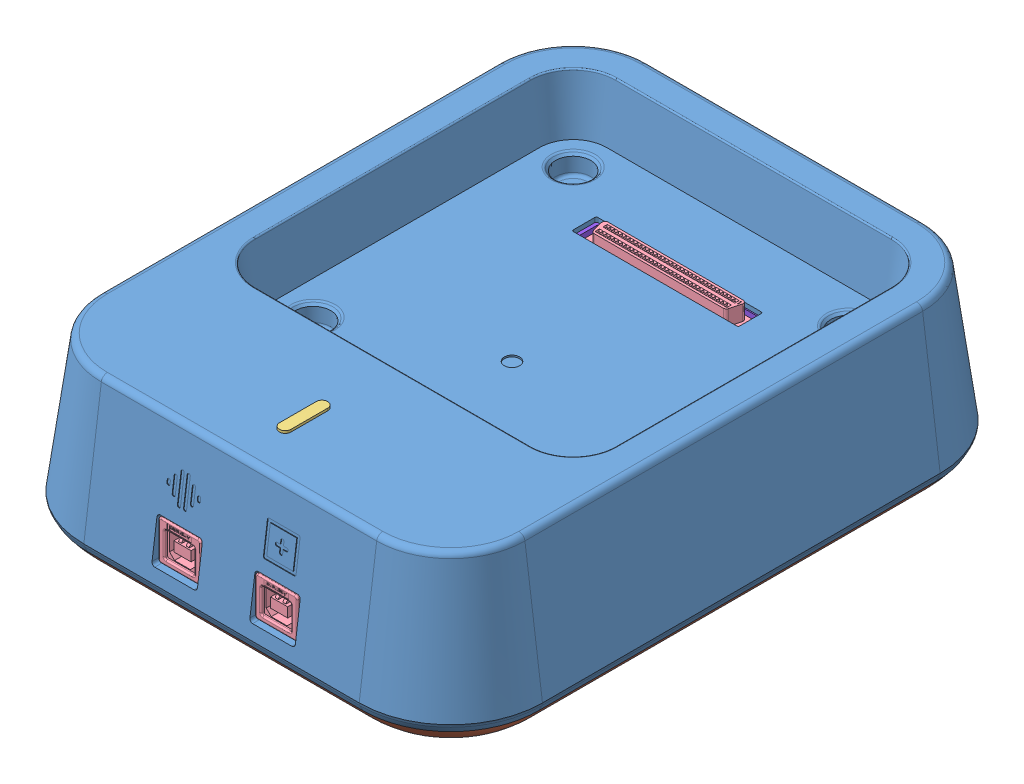
SolidWorks assembly 710-03064-01, configuration EXPLODE 1. Lengths in mm.
Overall size (149.92 60.49 189.92).
37 component instances, 15 part files, 52 mates.
Components (placement in the parent):
- 690-13322-01-1: 690-13322-01 [main top] at origin size (149.92 47.5 189.92)
- 690-13321-01-1: 690-13321-01 [amp bottom] at (0.0043 0.3144 -0.003) x (1 0 -0.000066) z (0.000066 0 1) size (147.12 44 187.12)
- 690-13335-01-1: 690-13335-01 [Default] at (0 42 68.125) x (0 0 -1) z (-1 0 0) size (40.5 22.51 15)
- 650-02461-01-2: 650-02461-01 [Default] at (37.5 19.7595 86.4) x (0 0 -1) z (0 1 0) size (161.48 77.75 25.95)
- 690-13430-01-4: 690-13430-01 [Default] at (-15.9372 11.6447 89.7779) x (0 -1 0) z (0 0 1) size (19.6 20.6 0.5)
- 690-13950-01-2: 690-13950-01 [Default] at (-1.9644 -41.2234 0.1742) size (194.82 1.78 194.82) (hidden)
- 690-13336-01-3: 690-13336-01 [Default] at (0.007 42 68.1256) x (0 0 -1) z (1 0 0) size (24.1 0.25 14.6)
- O-RING PLACE HOLDER-1: O-RING PLACE HOLDER [Default] at (5.773 -1.1006 6.1102) size (146.06 1.98 186.06)
- 690-13337-01-1: 690-13337-01 [Default] at (-0.132 23.2595 -50.5608) x (0.999997 0 -0.002288) z (0.002288 0 0.999997) size (68 5.5 14.5)
- 690-13430-01-5: 690-13430-01 [Default] at (15.7786 11.6447 89.878) x (0 -1 0) z (0 0 1) size (19.6 20.6 0.5)
- 250-06431-00-6: 250-06431-00 [99397A349] at (33.5 18.1525 -36.975) x (-0.159486 0 -0.9872) z (0 -1 0) size (5 5.25 8.76)
- 250-06431-00-8: 250-06431-00 [99397A349] at (33.5 18.1525 -64.5) x (-0.159486 0 -0.9872) z (0 -1 0) size (5 5.25 8.76)
- 250-06431-00-9: 250-06431-00 [99397A349] at (-33.5 18.1525 -36.975) x (0.943995 0 -0.329959) z (0 -1 0) size (5 5.25 8.76)
- 250-06431-00-10: 250-06431-00 [99397A349] at (-33.5 18.1525 -64.5) x (-0.159486 0 -0.9872) z (0 -1 0) size (5 5.25 8.76)
- 250-06431-00-11: 250-06431-00 [99397A349] at (33.5 18.1525 82.4) x (-0.159486 0 -0.9872) z (0 -1 0) size (5 5.25 8.76)
- 250-06431-00-13: 250-06431-00 [99397A349] at (-33.5 18.1525 82.4) x (-0.159486 0 -0.9872) z (0 -1 0) size (5 5.25 8.76)
- 250-06431-00-14: 250-06431-00 [99397A349] at (-33.5 18.1525 16.4) x (0.661999 0 0.749505) z (0 -1 0) size (5 5.25 8.76)
- 250-06431-00-17: 250-06431-00 [99397A349] at (33.5 18.1525 16.4) x (-0.159486 0 -0.9872) z (0 -1 0) size (5 5.25 8.76)
- 250-06430-00-6: 250-06430-00 [99397A484] at (-45 7.0739 -65) x (0.782317 0 -0.62288) z (0 -1 0) size (7 7.25 13.35)
- 250-06430-00-7: 250-06430-00 [99397A484] at (-44.9914 29.3144 65) x (0.782317 0 -0.62288) z (0 -1 0) size (7 7.25 13.35)
- 250-06430-00-11: 250-06430-00 [99397A484] at (45 7.0739 -65.0059) x (0.782317 0 -0.62288) z (0 -1 0) size (7 7.25 13.35)
- 250-06430-00-10: 250-06430-00 [99397A484] at (45.0086 29.3144 64.9941) x (0.782317 0 -0.62288) z (0 -1 0) size (7 7.25 13.35)
- 250-06431-00-1: 250-06431-00 [99397A349] at (-5 36.0263 82.6254) x (0.856632 0 0.515928) z (0 -1 0) size (5 5.25 8.76)
- 250-06431-00-2: 250-06431-00 [99397A349] at (5 36.0482 82.6254) x (-0.159486 0 -0.9872) z (0 -1 0) size (5 5.25 8.76)
- 250-06431-00-4: 250-06431-00 [99397A349] at (5 36.0507 48.125) x (-0.572843 0 -0.819665) z (0 -1 0) size (5 5.25 8.76)
- 250-06431-00-5: 250-06431-00 [99397A349] at (-5 36.0387 48.1246) x (0.649193 0 -0.760623) z (0 -1 0) size (5 5.25 8.76)
- 690-13338-01-2: 690-13338-01 [Default] at (45.0086 -11.4877 64.9941) x (0.945201 0 -0.326488) z (0.326488 0 0.945201) size (20 13 20)
- 690-13338-01-3: 690-13338-01 [Default] at (45 -11.4093 -65.0059) x (0.808095 0 -0.589052) z (0.589052 0 0.808095) size (20 13 20)
- 690-13338-01-4: 690-13338-01 [Default] at (-45 -11.4354 -65) x (0.796011 0 -0.605283) z (0.605283 0 0.796011) size (20 13 20)
- 690-13338-01-1: 690-13338-01 [Default] at (-44.9914 -11.3483 65) x (0.185576 0 -0.98263) z (0.98263 0 0.185576) size (20 13 20)
- 690-13885-01-1: 690-13885-01 [Default] at (45.0086 -4.7162 64.9941) size (18 0.5 18)
- 690-13885-01-2: 690-13885-01 [Default] at (45 -4.328 -65.0059) size (18 0.5 18)
- 690-13885-01-3: 690-13885-01 [Default] at (-45 -4.8227 -65) size (18 0.5 18)
- 690-13885-01-4: 690-13885-01 [Default] at (-44.9914 -2.7642 65) size (18 0.5 18)
- 961-00019-01-4: 961-00019-01 [Default] at (-0.2914 -12.1936 52.7077) x (-1 0 0.000066) z (0 -1 0) size (58.74 101.6 0.25)
  - 952-01439-01-1: 952-01439-01 [Default] at origin size (58.74 101.6 0.25)
  - 410-00892-00-1: 410-00892-00 [Default] at origin
Mates (geometry in assembly coordinates):
- Parallel2: parallel: plane of 650-02461-01-2 through (34.477 18.1525 86.397) normal (0 0 1); plane of assembly through (0 0 0) normal (0 0 1)
- Parallel3: parallel: plane of 650-02461-01-2 through (34.477 18.1525 86.397) normal (0 -1 0); plane of assembly through (0 0 0) normal (0 1 0)
- Concentric4: concentric: cylinder of 690-13337-01-1 through (30.8767 19.7595 -54.9003) axis (0 1 0) radius 2.9815; cylinder of 650-02461-01-2 through (30.8767 23.5822 -54.9003) axis (0 1 0) radius 1.016
- Coincident1: coincident: plane of 690-13337-01-1 through (-31.1407 19.7595 -46.2213) normal (0 -1 0); plane of 650-02461-01-2 through (34.477 19.7595 86.397) normal (0 1 0)
- Concentric5: concentric: circle of 690-13322-01-1; cone of 690-13335-01-1 through (5 38 82.6254) axis (0 -1 0)
- Concentric6: concentric: cone of 690-13322-01-1 through (-5 42 82.6254) axis (0 1 0); cone of 690-13335-01-1 through (-5 38 82.6254) axis (0 -1 0)
- Parallel10: parallel: plane of 690-13335-01-1 through (-7.5 42 76.1254) normal (0 1 0); plane of 690-13336-01-3 through (-6.293 42.25 55.326) normal (0 1 0)
- Parallel11: parallel: plane of 690-13335-01-1 through (7.5 42 68.125) normal (1 0 0); plane of 690-13336-01-3 through (7.307 42.25 77.426) normal (1 0 0)
- Coincident4: coincident: plane of 690-13335-01-1 through (-7.5 42 76.1254) normal (0 1 0); plane of 690-13336-01-3 through (-6.293 42 55.326) normal (0 -1 0)
- Distance1: distance = 0.193 mm: plane of 690-13336-01-3 through (7.307 42.25 77.426) normal (1 0 0); plane of 690-13335-01-1 through (7.5 42 68.125) normal (1 0 0)
- Distance2: distance = 0.1994 mm: line of 690-13336-01-3 through (-6.293 42 78.426) axis (1 0 0); line of 690-13335-01-1 through (-7.5 42 78.6254) axis (1 0 0)
- Coincident5: coincident: plane of 690-13322-01-1 through (0 38 130.7504) normal (0 -1 0); plane of 690-13335-01-1 through (-7.5 38 51.1246) normal (0 1 0)
- Concentric7: concentric: cone of 690-13322-01-1 through (-5 42 82.6254) axis (0 -1 0); cylinder of 250-06431-00-1 through (-5 33.9263 82.6254) axis (0 1 0) radius 2.5
- Concentric8: concentric: cone of 690-13322-01-1 through (5 42 82.6254) axis (0 -1 0); cylinder of 250-06431-00-2 through (5 33.9482 82.6254) axis (0 1 0) radius 2.5
- Concentric10: concentric: cone of 690-13322-01-1 through (5 42 48.125) axis (0 -1 0); cylinder of 250-06431-00-4 through (5 33.9507 48.125) axis (0 1 0) radius 2.5
- Coincident10: coincident: axis of 690-13335-01-1 through (-5 38 48.1246) axis (0 -1 0); axis of 250-06431-00-5 through (-5 33.348 48.1246) axis (0 1 0)
- Tangent1: tangent: plane of 690-13322-01-1 through (45 -0.11 91.0496) normal (0 -1 0); cylinder of O-RING PLACE HOLDER-1 through (45.0086 -1.1006 92.0402) axis (-1 0 0) radius 0.9906
- Coincident19: coincident: plane of 690-13322-01-1 through (33.5 19.7595 -37) normal (0 -1 0); plane of 650-02461-01-2 through (34.477 19.7595 86.397) normal (0 1 0)
- Concentric13: concentric: circle of 690-13322-01-1; cylinder of 650-02461-01-2 through (-33.5 18.1525 -64.5) axis (0 -1 0) radius 1.524
- Coincident20: coincident: axis of 650-02461-01-2 through (33.5 19.7595 -36.975) axis (0 -1 0); axis of 250-06431-00-6 through (33.5 15.4618 -36.975) axis (0 1 0)
- Coincident21: coincident: plane of 650-02461-01-2 through (34.477 18.1525 86.397) normal (0 -1 0); plane of 250-06431-00-6 through (33.5 18.1525 -36.975) normal (0 1 0)
- Coincident24: coincident: axis of 650-02461-01-2 through (-33.5 19.7595 -36.975) axis (0 -1 0); axis of 250-06431-00-9 through (-33.5 15.4618 -36.975) axis (0 1 0)
- Coincident25: coincident: plane of 650-02461-01-2 through (34.477 18.1525 86.397) normal (0 -1 0); plane of 250-06431-00-9 through (-33.5 18.1525 -36.975) normal (0 1 0)
- Coincident28: coincident: axis of 650-02461-01-2 through (33.5 19.7595 16.4) axis (0 -1 0); axis of 250-06431-00-17 through (33.5 16.3158 16.4) axis (0 1 0)
- Coincident29: coincident: plane of 650-02461-01-2 through (34.477 18.1525 86.397) normal (0 -1 0); plane of 250-06431-00-17 through (33.5 18.1525 16.4) normal (0 1 0)
- Coincident30: coincident: axis of 650-02461-01-2 through (-33.5 19.7595 16.4) axis (0 -1 0); axis of 250-06431-00-14 through (-33.5 15.4618 16.4) axis (0 1 0)
- Coincident31: coincident: plane of 650-02461-01-2 through (34.477 18.1525 86.397) normal (0 -1 0); plane of 250-06431-00-14 through (-33.5 18.1525 16.4) normal (0 1 0)
- Coincident32: coincident: axis of 650-02461-01-2 through (-33.5 19.7595 82.4) axis (0 -1 0); axis of 250-06431-00-13 through (-33.5 15.4618 82.4) axis (0 1 0)
- Coincident33: coincident: plane of 650-02461-01-2 through (34.477 18.1525 86.397) normal (0 -1 0); plane of 250-06431-00-13 through (-33.5 18.1525 82.4) normal (0 1 0)
- Coincident34: coincident: axis of 650-02461-01-2 through (33.5 19.7595 82.4) axis (0 -1 0); axis of 250-06431-00-11 through (33.5 16.3158 82.4) axis (0 1 0)
- Coincident35: coincident: plane of 650-02461-01-2 through (34.477 18.1525 86.397) normal (0 -1 0); plane of 250-06431-00-11 through (33.5 18.1525 82.4) normal (0 1 0)
- Coincident36: coincident: axis of 650-02461-01-2 through (-33.5 19.7595 -64.5) axis (0 -1 0); axis of 250-06431-00-10 through (-33.5 16.3158 -64.5) axis (0 1 0)
- Coincident37: coincident: plane of 650-02461-01-2 through (34.477 18.1525 86.397) normal (0 -1 0); plane of 250-06431-00-10 through (-33.5 18.1525 -64.5) normal (0 1 0)
- Coincident38: coincident: axis of 650-02461-01-2 through (33.5 19.7595 -64.5) axis (0 -1 0); axis of 250-06431-00-8 through (33.5 16.3158 -64.5) axis (0 1 0)
- Coincident39: coincident: plane of 650-02461-01-2 through (34.477 18.1525 86.397) normal (0 -1 0); plane of 250-06431-00-8 through (33.5 18.1525 -64.5) normal (0 1 0)
- Coincident40: coincident: axis of 690-13322-01-1 through (-45 0.2864 -65) axis (0 1 0); axis of 690-13321-01-1 through (-45 1.9644 -65) axis (0 -1 0)
- Coincident42: coincident: axis of 690-13321-01-1 through (-44.9914 1.9644 65) axis (0 -1 0); axis of O-RING PLACE HOLDER-1 through (-44.9914 6.8376 65) axis (0 -1 0)
- Concentric16: concentric: circle of 690-13321-01-1; circle of 250-06430-00-11
- Concentric17: concentric: circle of 690-13321-01-1; circle of 250-06430-00-10
- Concentric18: concentric: circle of 690-13321-01-1; circle of 250-06430-00-7
- Concentric19: concentric: circle of 690-13321-01-1; circle of 690-13338-01-1
- Concentric20: concentric: circle of 690-13321-01-1; circle of 690-13338-01-2
- Concentric21: concentric: circle of 690-13321-01-1; circle of 690-13338-01-2
- Concentric22: concentric: circle of 690-13321-01-1; circle of 690-13338-01-3
- Concentric23: concentric: circle of 690-13321-01-1; circle of 690-13338-01-4
- Coincident52: coincident: plane of 650-02461-01-2 through (37.5 19.7595 89.2779) normal (0 0 1); plane of 690-13430-01-4 through (-9.9372 6.1447 89.2779) normal (0 0 -1)
- Coincident54: coincident: plane of 650-02461-01-2 through (37.5 19.7595 89.378) normal (0 0 1); plane of 690-13430-01-5 through (21.7786 6.1447 89.378) normal (0 0 -1)
- Concentric24: concentric: circle of 690-13321-01-1; circle of 690-13885-01-1
- Concentric25: concentric: circle of 690-13321-01-1; circle of 690-13885-01-4
- Concentric26: concentric: circle of 690-13321-01-1; circle of 690-13885-01-2
- Concentric27: concentric: circle of 690-13321-01-1; circle of 690-13885-01-3
- Distance3: distance = 0.508 mm: plane of 961-00019-01-4 through (26.2283 -12.1936 47.6171) normal (0 1 0); plane of 690-13321-01-1 through (45 -11.6856 -65.0059) normal (0 -1 0)
